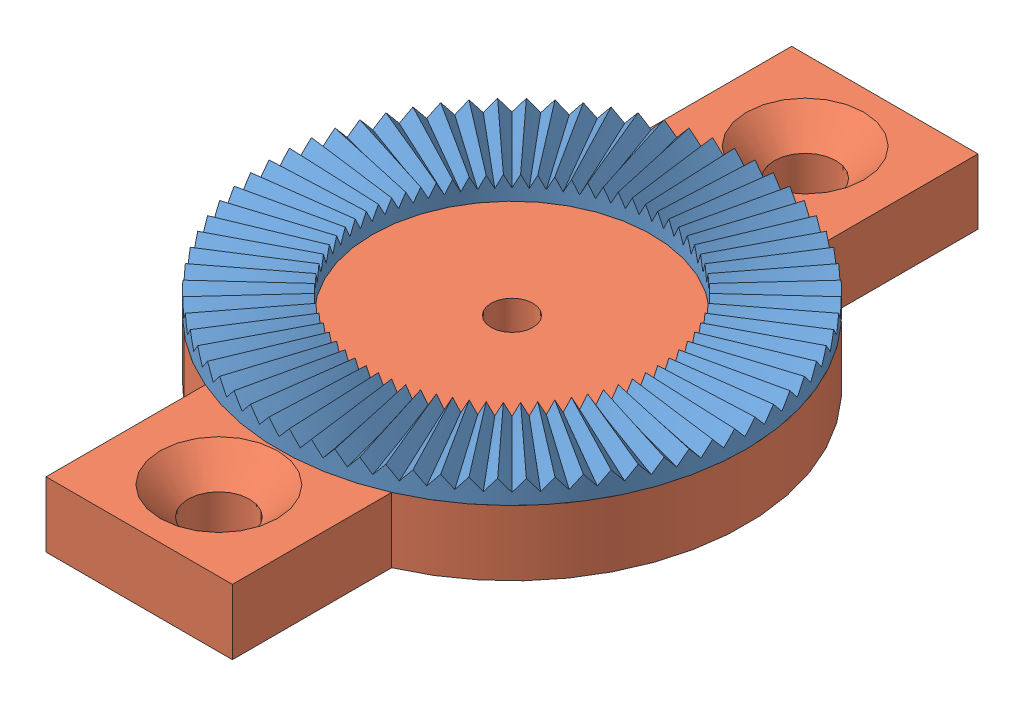
SolidWorks assembly Assem1, configuration Default. Lengths in mm.
Overall size (55 28.07 80).
2 component instances, 2 part files, 0 mates.
Components (placement in the parent):
- bevel4-1: bevel4 [Default] at origin size (55 28.07 50)
- saveingagain-1: saveingagain [Default] at (0 2.5 0) x (-1 0 0) z (0 -1 0) size (50 80 7)
